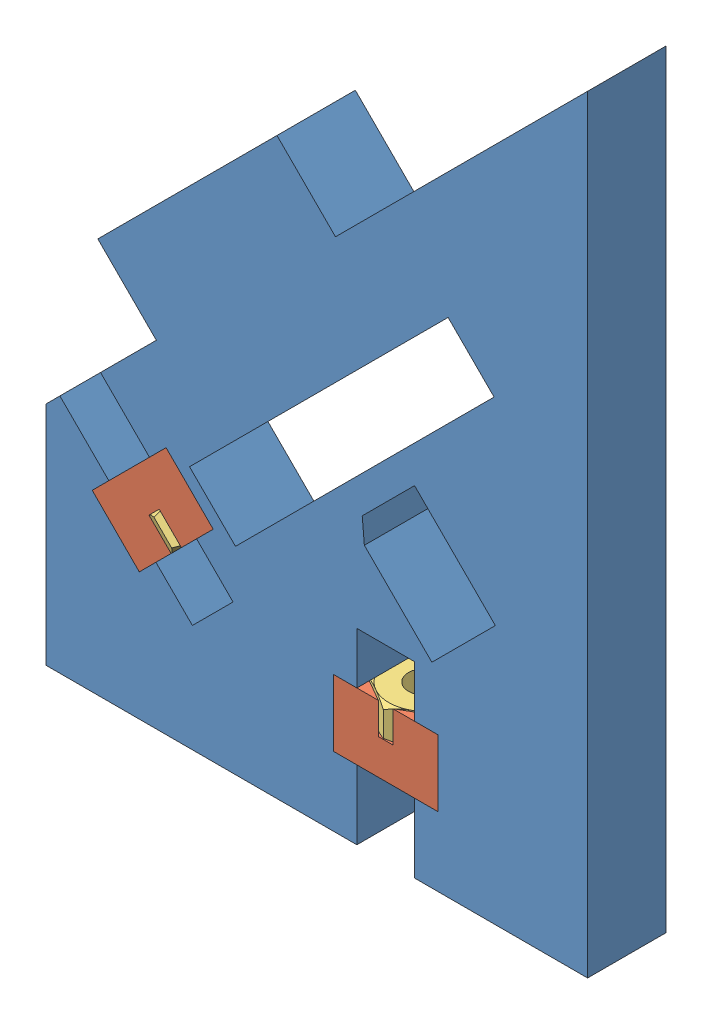
SolidWorks assembly Assembly lcd-support-b, configuration Valor predeterminado. Lengths in mm.
Overall size (41.47 58.8 7.94).
7 component instances, 3 part files, 6 mates.
Components (placement in the parent):
- lcd-support-b-1: lcd-support-b [Valor predeterminado] at (-52.9032 -42.0267 55.8) size (41.47 58.8 6)
- Assembly m3-nut-adapter + Nut DIN 934 - M3-1: Assembly m3-nut-adapter + Nut DIN 934 - M3 [Valor predeterminado] at (5.2665 -27.8591 58.8) x (1 0 0) z (0 1 0) size (8.25 7.94 5.1)
  - m3-nut-adapter-1: m3-nut-adapter [Valor predeterminado] at origin size (8 6 5.1)
  - Nut DIN 934 - M3-1: Nut DIN 934 - M3 [Valor predeterminado] at (0 0 3.9) x (0 0 1) z (-0.866025 -0.5 0) size (2.4 5.5 6.35)
- Assembly m3-nut-adapter + Nut DIN 934 - M3-2: Assembly m3-nut-adapter + Nut DIN 934 - M3 [Valor predeterminado] at (-14.3695 -16.9574 58.8) x (0.707107 0.707107 0) z (0.707107 -0.707107 0) size (8.25 7.94 5.1)
  - m3-nut-adapter-1: m3-nut-adapter [Valor predeterminado] at origin size (8 6 5.1)
  - Nut DIN 934 - M3-1: Nut DIN 934 - M3 [Valor predeterminado] at (0 0 3.9) x (0 0 1) z (-0.866025 -0.5 0) size (2.4 5.5 6.35)
Mates (geometry in assembly coordinates):
- Coincidente1: coincident: plane of assembly; plane of assembly; plane of lcd-support-b-1 through (-52.9032 -42.0267 61.8) normal (0 0 1); plane of Assembly m3-nut-adapter + Nut DIN 934 - M3-1/m3-nut-adapter-1 through (1.2665 -22.7591 61.8) normal (0 0 1)
- Coincidente2: coincident: plane of assembly; plane of assembly; plane of lcd-support-b-1 through (1.2665 -27.8591 61.8) normal (1 0 0); plane of Assembly m3-nut-adapter + Nut DIN 934 - M3-1/m3-nut-adapter-1 through (1.2665 -22.7591 55.8) normal (-1 0 0)
- Coincidente3: coincident: plane of assembly; plane of assembly; plane of lcd-support-b-1 through (9.2665 -27.8591 61.8) normal (0 1 0); plane of Assembly m3-nut-adapter + Nut DIN 934 - M3-1/m3-nut-adapter-1 through (5.2665 -27.8591 58.8) normal (0 -1 0)
- Coincidente4: coincident: plane of assembly; plane of assembly; plane of lcd-support-b-1 through (-52.9032 -42.0267 61.8) normal (0 0 1); plane of Assembly m3-nut-adapter + Nut DIN 934 - M3-2/m3-nut-adapter-1 through (-13.5917 -23.3921 61.8) normal (0 0 1)
- Coincidente5: coincident: plane of assembly; plane of assembly; plane of lcd-support-b-1 through (-7.9348 -17.7352 61.8) normal (-0.707107 -0.707107 0); plane of Assembly m3-nut-adapter + Nut DIN 934 - M3-2/m3-nut-adapter-1 through (-7.9348 -17.7352 61.8) normal (0.707107 0.707107 0)
- Coincidente6: coincident: plane of assembly; plane of assembly; plane of lcd-support-b-1 through (-11.5411 -14.129 61.8) normal (0.707107 -0.707107 0); plane of Assembly m3-nut-adapter + Nut DIN 934 - M3-2/m3-nut-adapter-1 through (-14.3695 -16.9574 58.8) normal (-0.707107 0.707107 0)
